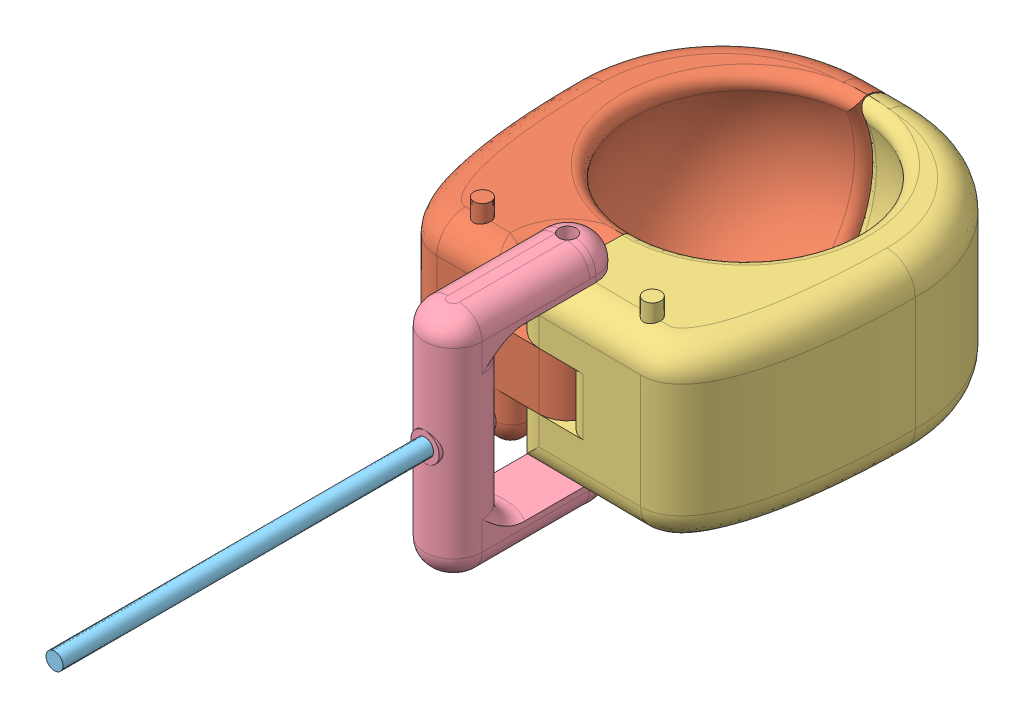
SolidWorks assembly Assem2, configuration Default. Lengths in mm.
Overall size (62.43 40 147.14).
5 component instances, 5 part files, 13 mates.
Components (placement in the parent):
- dowel-1: dowel [Default] at origin size (3 30 3)
- left gripper-1: left gripper [Default] at (-14.8819 0 -26.0678) x (0.99999 0 0.004537) z (-0.004537 0 0.99999) size (35.81 33.31 62.81)
- right gripper-1: right gripper [Default] at (15.2281 0 -25.8671) x (-0.999961 0 -0.008794) z (-0.008794 0 0.999961) size (36.1 33.37 63.1)
- Claw wrist-1: Claw wrist [Default] at (0 15 20) x (1 0 0) z (0 1 0) size (10 30 40)
- silver steel arm-1: silver steel arm [Default] at (2.2998 0.9802 15) x (-0.392068 0.919936 0) z (0 0 1) size (3 3 75)
Mates (geometry in assembly coordinates):
- Concentric1: concentric anti-aligned: cylinder of dowel-1 through (0 15 0) axis (0 -1 0) radius 1.5; cylinder of left gripper-1 through (0 -15 0) axis (0 1 0) radius 1.5
- Concentric2: concentric aligned: cylinder of dowel-1 through (0 15 0) axis (0 -1 0) radius 1.5; cylinder of right gripper-1 through (0 15 0) axis (0 -1 0) radius 1.5
- Coincident1: coincident aligned: plane of left gripper-1 through (-28.0133 15 2.8729) normal (0 1 0); plane of right gripper-1 through (27.9725 15 3.2461) normal (0 1 0)
- Coincident2: coincident aligned: plane of dowel-1 through (0 15 0) normal (0 1 0); plane of right gripper-1 through (27.9725 15 3.2461) normal (0 1 0)
- Coincident3: coincident aligned: plane of dowel-1 through (0 0 0) normal (0 0 1); plane of assembly through (0 0 0) normal (0 0 1)
- Coincident4: coincident aligned: plane of dowel-1 through (0 0 0) normal (0 1 0); plane of assembly through (0 0 0) normal (0 1 0)
- Coincident5: coincident aligned: plane of dowel-1 through (0 0 0) normal (1 0 0); plane of assembly through (0 0 0) normal (1 0 0)
- GearMate1: gear = 10 : 10 mm: cylinder of left gripper-1 through (0 -26.1803 0) axis (0 1 0) radius 5; cylinder of right gripper-1 through (0 26.1803 0) axis (0 -1 0) radius 5
- Coincident13: coincident anti-aligned: plane of right gripper-1 through (27.9725 -15 3.2461) normal (0 -1 0); plane of Claw wrist-1 through (0 -15 0) normal (0 1 0)
- Concentric3: concentric aligned: cylinder of dowel-1 through (0 15 0) axis (0 -1 0) radius 1.5; cylinder of Claw wrist-1 through (0 20 0) axis (0 -1 0) radius 1.5
- Coincident14: coincident aligned: plane of Claw wrist-1 through (0 15 20) normal (1 0 0); plane of assembly through (0 0 0) normal (1 0 0)
- Concentric4: concentric: cylinder of Claw wrist-1 through (0 0 -5) axis (0 0 1) radius 1.475; cylinder of silver steel arm-1 through (0 0 133.8013) axis (0 0 -1) radius 1.5
- Coincident15: coincident aligned: plane of Claw wrist-1 through (0 0 15) normal (0 0 -1); plane of silver steel arm-1 through (0 0 15) normal (0 0 -1)
